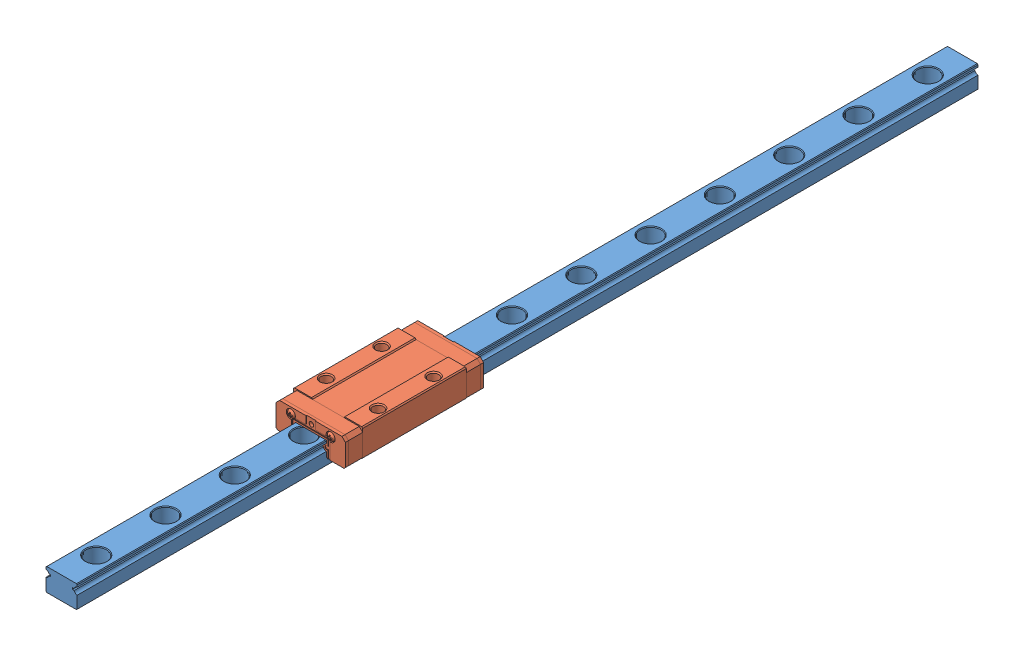
SolidWorks assembly MGN9H-250, configuration По умолчанию. Lengths in mm.
2 component instances, 2 part files, 3 mates.
Components (placement in the parent):
- MGNR9-1: MGNR9 [По умолчанию] at origin size (9 6.5 220)
- MGN9H-1: MGN9H [По умолчанию] at (0 2.75 168.1409) size (20 8 40.67)
Mates (geometry in assembly coordinates):
- 重合/共線/共點1: coordinate: point of MGNR9-1
- 同軸心1: concentric: cylinder of MGNR9-1 through (4.6 1.45 220) axis (0 0 -1) radius 1; cylinder of MGN9H-1 through (4.6 1.45 188.0919) axis (0 0 -1) radius 1
- 同軸心2: concentric: cylinder of MGNR9-1 through (-4.6 1.45 220) axis (0 0 -1) radius 1; cylinder of MGN9H-1 through (-4.6 1.45 188.0919) axis (0 0 -1) radius 1
